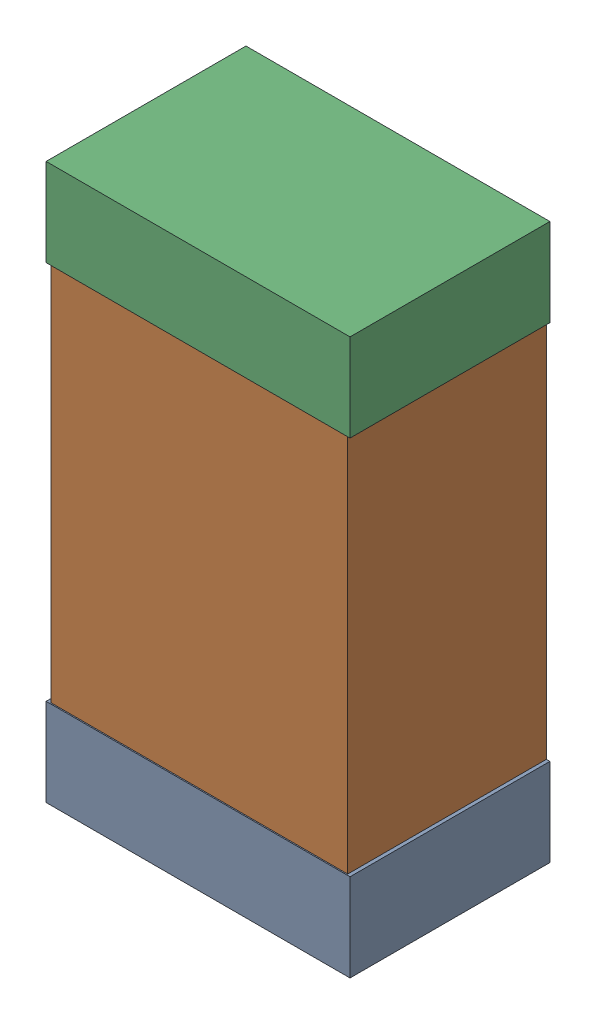
SolidWorks assembly R10Kanaloa_v2.0.0_GPIO_b, configuration Default. Lengths in mm.
Overall size (1.3 2.38 0.85).
6 component instances, 2 part files, 0 mates.
Components (placement in the parent):
- 330415056-1: 330415056 [Default] at (73.66 129.175 0) size (1.3 0.38 0.85)
  - Extruded_2-1: Extruded_2 [Default] at origin size (1.3 0.38 0.85)
- 352877008-1: 352877008 [Default] at (73.66 130.175 0) size (1.27 2.2 0.85)
  - Extruded_3-1: Extruded_3 [Default] at origin size (1.27 2.2 0.85)
- 330415056-2: 330415056 [Default] at (73.66 131.175 0) size (1.3 0.38 0.85)
  - Extruded_2-1: Extruded_2 [Default] at origin size (1.3 0.38 0.85)
